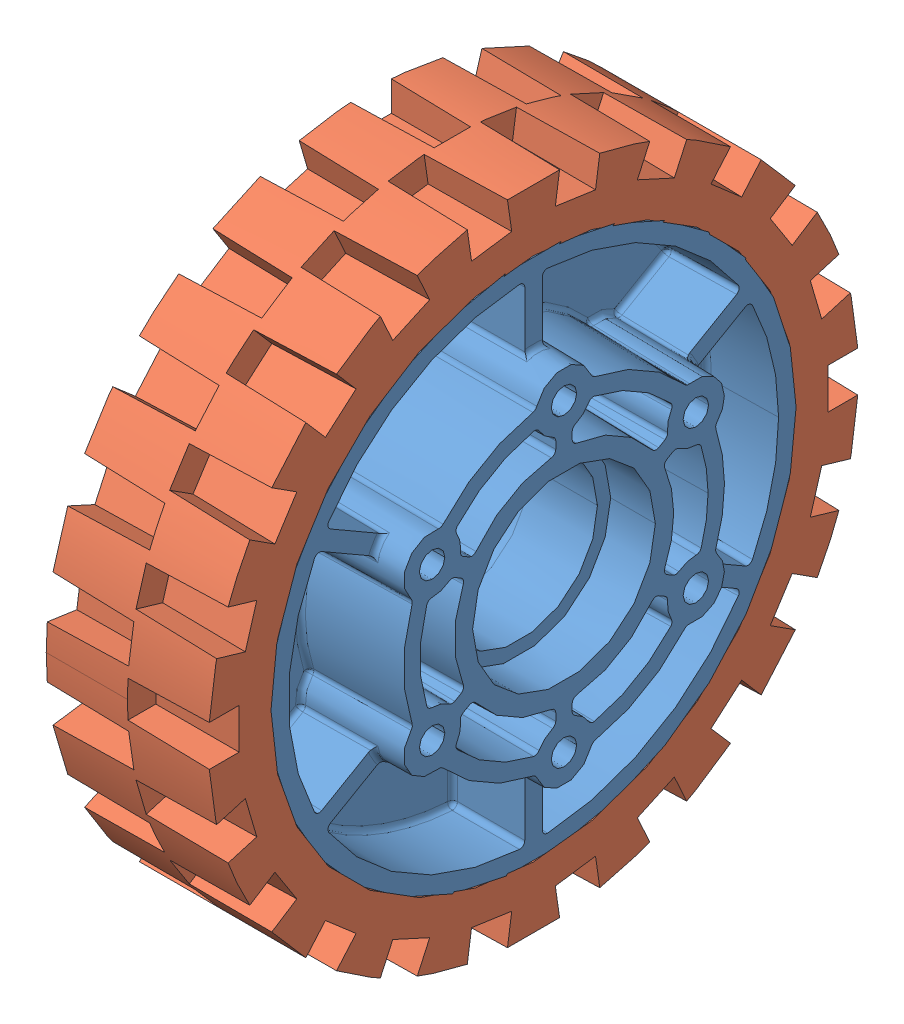
SolidWorks assembly am-2256 4 in HiGrip Wheel(2)^am-2256 4 in HiGrip Wheel, configuration Default. Lengths in mm.
Overall size (35.12 101.6 101.6).
2 component instances, 2 part files, 0 mates.
Components (placement in the parent):
- 4in 2013 Hub-1: 4in 2013 Hub [Default] at (-8.0517 2.5236 2.5343) size (35.12 82.55 82.55)
- 4 in tread-1: 4 in tread [Default] at (-8.0517 2.5236 2.5343) size (25.4 101.6 101.6)
